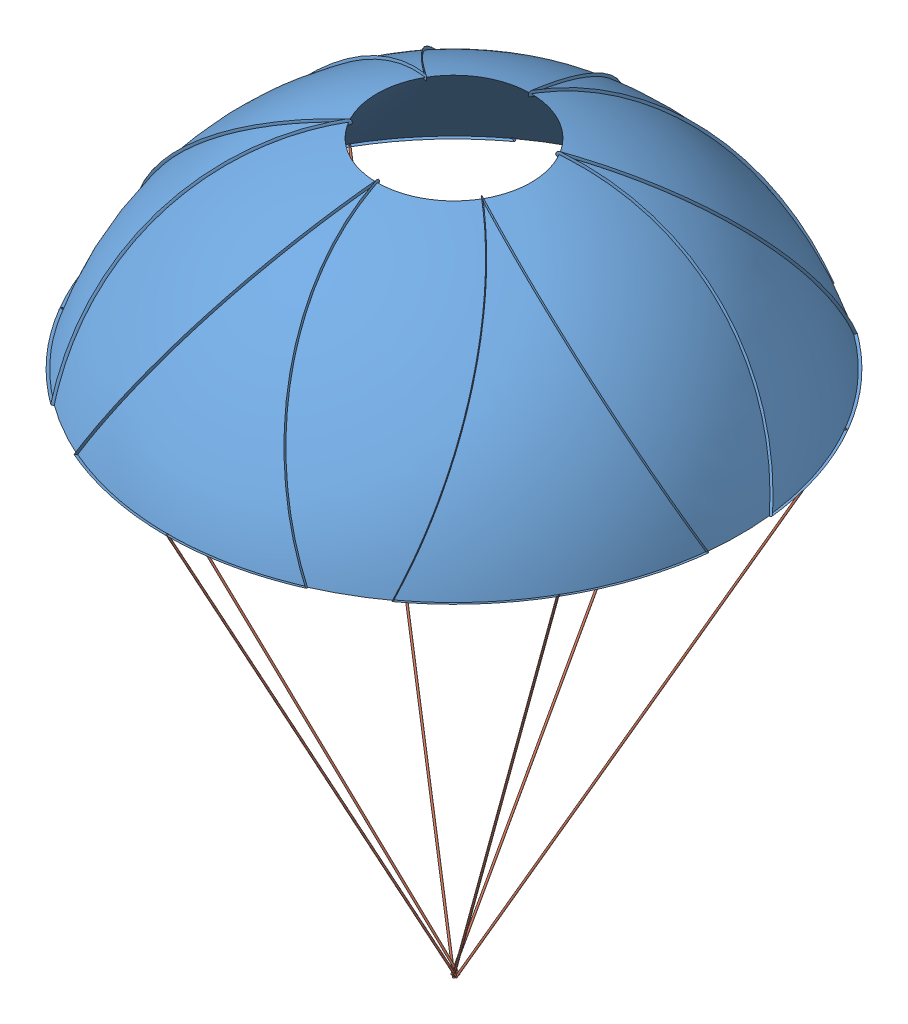
SolidWorks assembly parashute_ass, configuration Default. Lengths in mm.
Overall size (675.35 856.16 675.01).
7 component instances, 2 part files, 6 mates.
Components (placement in the parent):
- parashute-1: parashute [Default] at (-53.8101 192.378 639.2758) size (675.35 248.37 675.01)
- the rope-1: the rope [Default] at (236.5838 297.7106 471.6165) x (-0.555933 0.450381 0.698638) z (-0.412091 -0.879264 0.238907) size (2 2 700)
- the rope-2: the rope [Default] at (-53.8111 297.051 974.5958) x (-0.960241 -0.136091 0.243755) z (0.002519 -0.877322 -0.479895) size (2 2 700)
- the rope-3: the rope [Default] at (-54.5724 -317.8882 639.0054) x (-0.61093 0.461937 -0.642945) z (0.413464 0.878737 0.238472) size (2 2 700)
- the rope-4: the rope [Default] at (-53.8096 297.7154 303.955) x (0.936138 -0.170382 -0.307598) z (-0.001471 -0.876658 0.481112) size (2 2 700)
- the rope-5: the rope [Default] at (-53.8065 -319.2172 639.3363) x (-0.910704 -0.404706 0.082657) z (-0.412379 0.879328 -0.238171) size (2 2 700)
- the rope-6: the rope [Default] at (-50.2158 -315.1186 637.2002) x (0.611688 0.075933 0.787447) z (-0.422151 0.873146 0.24373) size (2 2 700)
Mates (geometry in assembly coordinates):
- Tangent1: tangent: circle of the rope-2; curve of parashute-1
- Tangent2: tangent: curve of parashute-1; circle of the rope-6
- Tangent3: tangent: curve of parashute-1; circle of the rope-5
- Tangent4: tangent: curve of parashute-1; circle of the rope-4
- Tangent5: tangent: curve of parashute-1; circle of the rope-1
- Tangent6: tangent: curve of parashute-1; circle of the rope-3
